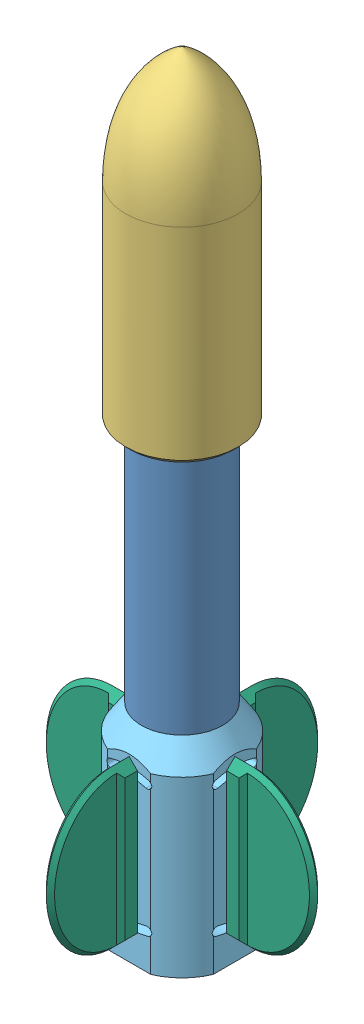
SolidWorks assembly Colander Assembely, configuration Default. Lengths in mm.
Overall size (163.92 463.09 163.92).
9 component instances, 6 part files, 16 mates.
Components (placement in the parent):
- Colander rocket-1: Colander rocket [Default] at (133.4421 -1.759 322.8892) size (49 400 49)
- Colander rocket Static electronics mount Rev1 26.11.22-1: Colander rocket Static electronics mount Rev1 26.11.22 [Default] at (133.4421 290.9312 322.8892) x (1 0 0) z (0 1 0) size (51.62 26.5 136)
- Colander Rocket Top cap 03.12.22-1: Colander Rocket Top cap 03.12.22 [Default] at (133.4421 265.6927 322.8892) size (68 195.64 68)
- Colander Rocket Top Cap Push Rod-1: Colander Rocket Top Cap Push Rod [Default] at (133.4421 390.6927 322.8892) x (0.999934 0 0.011477) z (0.011477 0 -0.999934) size (52 128.01 52)
- Colander rocket Finn mount 17.01.23-1: Colander rocket Finn mount 17.01.23 [Default] at (133.4421 -1.759 322.8892) size (64.2 120 64.2)
- Colander rocket Finn 21.01.23-2: Colander rocket Finn 21.01.23 [Default] at (165.3991 10.741 327.8892) x (0 -1 0) z (0 0 1) size (95.01 50.01 10)
- Colander rocket Finn 21.01.23-3: Colander rocket Finn 21.01.23 [Default] at (128.4421 10.741 354.8462) x (0 -1 0) z (-1 0 0) size (95.01 50.01 10)
- Colander rocket Finn 21.01.23-5: Colander rocket Finn 21.01.23 [Default] at (101.4851 105.741 327.8892) x (0 1 0) z (0 0 1) size (95.01 50.01 10)
- Colander rocket Finn 21.01.23-6: Colander rocket Finn 21.01.23 [Default] at (138.4421 10.741 290.9322) x (0 -1 0) z (1 0 0) size (95.01 50.01 10)
Mates (geometry in assembly coordinates):
- Concentric3: concentric aligned: cylinder of Colander rocket-1 through (133.4421 398.241 322.8892) axis (0 -1 0) radius 24.5; cylinder of Colander rocket Static electronics mount Rev1 26.11.22-1 through (133.4421 415.9312 322.8892) axis (0 -1 0) radius 25
- Coincident7: coincident anti-aligned: plane of Colander Rocket Top cap 03.12.22-1 through (133.4421 390.6927 322.8892) normal (0 -1 0); plane of Colander Rocket Top Cap Push Rod-1 through (133.4421 390.6927 322.8892) normal (0 1 0)
- Concentric5: concentric anti-aligned: cylinder of Colander Rocket Top cap 03.12.22-1 through (133.4421 390.6927 322.8892) axis (0 -1 0) radius 26.5; cylinder of Colander Rocket Top Cap Push Rod-1 through (133.4421 387.6927 322.8892) axis (0 1 0) radius 26
- Concentric7: concentric aligned: cylinder of Colander rocket Static electronics mount Rev1 26.11.22-1 through (133.4421 415.9312 322.8892) axis (0 -1 0) radius 26.5; cylinder of Colander Rocket Top cap 03.12.22-1 through (133.4421 390.6927 322.8892) axis (0 -1 0) radius 26.5
- Concentric8: concentric aligned: cylinder of Colander rocket-1 through (133.4421 398.241 322.8892) axis (0 -1 0) radius 24.5; cylinder of Colander rocket Finn mount 17.01.23-1 through (133.4421 118.241 322.8892) axis (0 -1 0) radius 24.5
- Coincident10: coincident aligned: plane of Colander rocket-1 through (133.4421 -1.759 322.8892) normal (0 -1 0); plane of Colander rocket Finn mount 17.01.23-1 through (133.4421 -1.759 322.8892) normal (0 -1 0)
- Concentric9: concentric anti-aligned: circle of Colander rocket Finn mount 17.01.23-1; circle of Colander rocket Finn 21.01.23-2
- Coincident11: coincident anti-aligned: plane of Colander rocket Finn mount 17.01.23-1 through (165.3991 -1.759 322.8892) normal (1 0 0); plane of Colander rocket Finn 21.01.23-2 through (165.3991 10.741 327.8892) normal (-1 0 0)
- Coincident12: coincident anti-aligned: circle of Colander rocket Finn mount 17.01.23-1; plane of Colander rocket Finn 21.01.23-3 through (128.4421 10.741 354.8462) normal (0 0 -1)
- Concentric10: concentric anti-aligned: circle of Colander rocket Finn mount 17.01.23-1; circle of Colander rocket Finn 21.01.23-3
- Parallel1: parallel anti-aligned: plane of Colander rocket Finn 21.01.23-3 through (130.9421 105.741 354.8462) normal (-1 0 0)
- Coincident16: coincident anti-aligned: plane of Colander rocket Finn mount 17.01.23-1 through (101.4851 -1.759 322.8892) normal (-1 0 0); plane of Colander rocket Finn 21.01.23-5 through (101.4851 105.741 327.8892) normal (1 0 0)
- Concentric12: concentric aligned: circle of Colander rocket Finn mount 17.01.23-1; circle of Colander rocket Finn 21.01.23-5
- Coincident17: coincident anti-aligned: plane of Colander rocket Finn mount 17.01.23-1 through (133.4421 -1.759 290.9322) normal (0 0 -1); plane of Colander rocket Finn 21.01.23-6 through (138.4421 10.741 290.9322) normal (0 0 1)
- Concentric13: concentric aligned: circle of Colander rocket Finn mount 17.01.23-1; circle of Colander rocket Finn 21.01.23-6
- Parallel2: parallel anti-aligned: plane of Colander rocket Finn 21.01.23-6 through (130.9421 105.741 290.9322) normal (-1 0 0)
